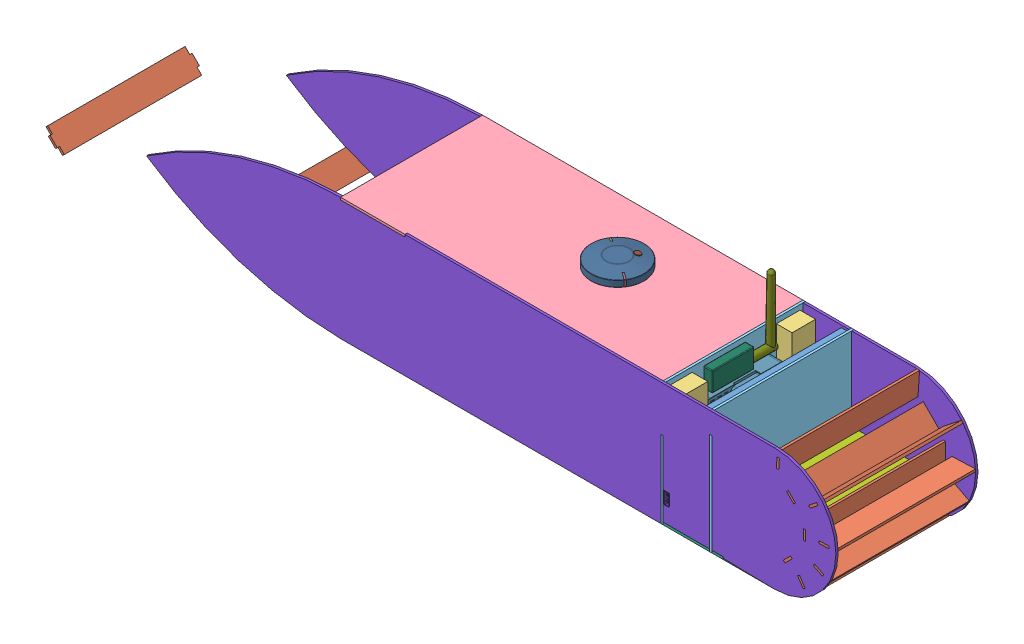
SolidWorks assembly payload_assembly, configuration Default. Lengths in mm.
Overall size (902.45 257.73 438.02).
36 component instances, 21 part files, 60 mates.
Components (placement in the parent):
- payload_box-1: payload_box [Default] at origin size (305 130 155)
- payload_parachute-1: payload_parachute [Default] at (305 0 0) x (0 0 -1) z (1 0 0) size (155 130 80)
- plates_payload_spacer-1: plates_payload_spacer [Default] at (-10 -10 10) x (0 0 -1) z (0 -1 0) size (175 405 150)
- plate_top-1: plate_top [Default] at (-10 140 10) x (0 0 1) z (0 1 0) size (181 411 3)
- plate_vertical-1: plate_vertical [Default] at (385 0 0) x (0 0 -1) z (1 0 0) size (181 156 3)
- plate_horizontal_front-1: plate_horizontal_front [Default] at (395 -13 13) size (144.93 3 181)
- battery-1: battery [Default] at (459.93 -89.8623 1.4153) x (0 0 -1) z (1 0 0) size (170 50 80)
- plate_side-2: plate_side [Default] at (-260.0699 -13 -168) x (1 0 0) z (0 -1 0) size (878 3 156)
- plate_side-5: plate_side [Default] at (-260.0699 -13 10) x (1 0 0) z (0 -1 0) size (878 3 156)
- Buzzer-1: Buzzer [Default] at (398 15.3505 -147.1593) x (0 -1 0) z (0 0 1) size (44.4 5.16 29.86)
- HERE GPS-1: HERE GPS [Default] at (243.7386 143 -83.1609) x (-0.837169 0 -0.546944) z (0 1 0) size (67.24 67.23 17.04)
  - HERE GPS.iges-1: HERE GPS.iges [Default] at origin size (67.24 67.23 17.04)
    - Component1.iges-1: Component1.iges [Default] at origin size (67.22 67.23 16.8)
    - Component2.iges-1: Component2.iges [Default] at origin size (8.5 8.84 4.72)
    - Component3.iges-1: Component3.iges [Default] at origin size (8.53 2.03 12.07)
    - Component5.iges-1: Component5.iges [Default] at origin size (8.63 2.03 12.07)
- Pixhawk2.1 CUBE with Edison carrier-1: Pixhawk2.1 CUBE with Edison carrier [Default] at (398 86.4256 -77.5) x (0 0 -1) z (1 0 0) size (94.25 44.2 30.94)
- Transmitter-1: Transmitter [Default] at (409.5873 129.6354 -50.6064) x (0 0 1) z (0 -1 0) size (85.99 11.87 93.47)
  - Transmitter Body-1: Transmitter Body [Default] at (-14.2095 0.1873 5.1078) size (59.4 11.4 25)
  - Transmitter Antenna-1: Transmitter Antenna [Default] at (-41.6595 7.0523 10.0828) x (0 -0.010581 -0.999944) z (0 0.999944 -0.010581) size (90.85 31.89 9.9)
- XT60E-M-1: XT60E-M [Default] at (402.1 17.8234 6) size (8.2 27.2 16.5)
- RaspberryPi as part-1: RaspberryPi as part [Default] at (401 18 -77.5) x (0 0 1) z (0 1 0) size (89.62 18.75 58.3)
- plate_vertical-2: plate_vertical [Default] at (446.93 0 0) x (0 0 -1) z (1 0 0) size (181 156 3)
- electronics_cushion-1: electronics_cushion [Default] at (456.93 -10 -165) x (0 0 1) z (0 -1 0) size (175 10 150)
- support_plates-1: support_plates [Default] at (570.2912 87.207 13) x (0 0 -1) z (0.707107 0.707107 0) size (181 30 3)
- ESC-3: ESC [Default] at (398 136.8447 -131.1379) x (0 -1 0) z (0 0 1) size (90 20 30)
- ESC-5: ESC [Default] at (398 136.8447 6.1379) x (0 -1 0) z (0 0 1) size (90 20 30)
- support_plates-7: support_plates [Default] at (579.3866 80.8169 13) x (0 0 -1) z (-1 0 0) size (181 30 3)
- support_plates-9: support_plates [Default] at (567.1217 25.4338 13) x (0 0 -1) z (-0.841434 -0.540359 0) size (181 30 3)
- support_plates-12: support_plates [Default] at (587.8173 68.4184 13) x (0 0 -1) z (0.040003 -0.9992 0) size (181 30 3)
- support_plates-14: support_plates [Default] at (583.2011 44.2036 13) x (0 0 -1) z (-0.461126 -0.887335 0) size (181 30 3)
- support_plates-15: support_plates [Default] at (576.5975 95.9898 13) x (0 0 -1) z (0.621321 -0.783556 0) size (181 30 3)
- support_plates-16: support_plates [Default] at (541.5439 112.9819 13) x (0 0 -1) z (0.997897 -0.064824 0) size (181 30 3)
- support_plates-19: support_plates [Default] at (568.3493 37.745 13) x (0 0 -1) z (-0.707107 0.707107 0) size (181 30 3)
- support_plates-20: support_plates [Default] at (-263.3078 115.5649 119.621) x (0 0 -1) z (0.707107 0.707107 0) size (181 30 3)
- support_plates-21: support_plates [Default] at (-217.4292 -52.2343 -137.4006) x (0 0 -1) z (0.707107 0.707107 0) size (181 30 3)
Mates (geometry in assembly coordinates):
- InPlace1: in place: plane of payload_box-1 through (305 130 0) normal (1 0 0); plane of payload_parachute-1 through (305 0 0) normal (1 0 0); moOrthogonalPlaneRef_w of payload_box-1 through (305 130 0) normal (1 0 0); plane of payload_parachute-1 through (305 0 0) normal (0 1 0); plane of payload_box-1 through (305 130 0) normal (1 0 0); plane of payload_parachute-1 through (305 0 0) normal (0 0 -1); plane of payload_box-1 through (305 130 0) normal (1 0 0); unknown of payload_parachute-1
- Coincident1: coincident aligned: plane of ?; plane of ?
- Coincident2: coincident aligned: moOrthogonalPlaneRef_w of payload_box-1 through (305 0 0) normal (0 1 0); plane of Part2^Assem1-1 through (305 0 0) normal (0 1 0)
- Coincident3: coincident anti-aligned: moOrthogonalPlaneRef_w of payload_box-1 through (305 0 0) normal (0 0 1); plane of Part2^Assem1-1 through (305 0 0) normal (0 0 -1)
- Width1: width anti-aligned: plane of plates_payload_spacer-1 through (395 -10 -165) normal (0 0 -1); plane of payload_box-1 through (395 -10 10) normal (0 0 1); plane of plates_payload_spacer-1 through (0 130 0) normal (0 0 1); plane of payload_box-1 through (0 130 -155) normal (0 0 -1)
- Width2: width anti-aligned: plane of plates_payload_spacer-1 through (395 -10 10) normal (0 -1 0); plane of payload_box-1 through (395 140 10) normal (0 1 0); plane of plates_payload_spacer-1 through (0 130 0) normal (0 1 0); plane of payload_box-1 through (0 0 0) normal (0 -1 0)
- Width3: width anti-aligned: plane of plates_payload_spacer-1 through (-10 -10 10) normal (-1 0 0); plane of payload_parachute-1 through (395 -10 10) normal (1 0 0); plane of plates_payload_spacer-1 through (385 0 0) normal (1 0 0); plane of payload_box-1 through (0 130 0) normal (-1 0 0)
- InPlace2: in place: plane of plates_payload_spacer-1 through (395 140 10) normal (0 1 0); plane of ? through (0 140 0) normal (0 1 0); plane of plates_payload_spacer-1 through (395 140 10) normal (0 1 0); plane of ? through (0 140 0) normal (0 0 -1); plane of plates_payload_spacer-1 through (395 140 10) normal (0 1 0); plane of ? through (0 140 0) normal (1 0 0); plane of plates_payload_spacer-1 through (395 140 10) normal (0 1 0); unknown of plate_top-1
- Coincident4: coincident aligned: plane of ?; plane of ?
- Coincident5: coincident aligned: moOrthogonalPlaneRef_w of plates_payload_spacer-1 through (-10 140 10) normal (1 0 0); plane of plate_top-1 through (-10 140 10) normal (1 0 0)
- Coincident6: coincident anti-aligned: moOrthogonalPlaneRef_w of plates_payload_spacer-1 through (-10 140 10) normal (0 0 -1); plane of plate_top-1 through (-10 140 10) normal (0 0 1)
- InPlace3: in place: plane of payload_parachute-1 through (385 0 0) normal (1 0 0); plane of plate_vertical-1 through (385 0 0) normal (1 0 0); plane of payload_parachute-1 through (385 0 0) normal (1 0 0); plane of plate_vertical-1 through (385 0 0) normal (0 1 0); plane of payload_parachute-1 through (385 0 0) normal (1 0 0); plane of plate_vertical-1 through (385 0 0) normal (0 0 -1); plane of payload_parachute-1 through (385 0 0) normal (1 0 0); unknown of plate_vertical-1
- Coincident7: coincident aligned: plane of ?; plane of ?
- Coincident8: coincident aligned: moOrthogonalPlaneRef_w of payload_parachute-1 through (385 0 0) normal (0 1 0); plane of Part5^payload_assembly-1 through (385 0 0) normal (0 1 0)
- Coincident9: coincident anti-aligned: moOrthogonalPlaneRef_w of payload_parachute-1 through (385 0 0) normal (0 0 1); plane of Part5^payload_assembly-1 through (385 0 0) normal (0 0 -1)
- Coincident10: coincident aligned: plane of Part5^payload_assembly-1 through (398 -13 13) normal (0 -1 0); plane of plate_horizontal_front-1 through (395 -13 13) normal (0 -1 0)
- Coincident11: coincident aligned: plane of Part5^payload_assembly-1 through (398 -13 -168) normal (0 0 -1); plane of plate_horizontal_front-1 through (395 -10 -168) normal (0 0 -1)
- Coincident12: coincident aligned: plane of Part5^payload_assembly-1 through (395 0 0) normal (-1 0 0); plane of plate_horizontal_front-1 through (395 -10 13) normal (-1 0 0)
- Coincident14: coincident anti-aligned: plane of plates_payload_spacer-1 through (395 -10 -165) normal (0 0 -1); plane of plate_side-2 through (539.9301 65 -165) normal (0 0 1)
- Coincident15: coincident aligned: plane of plate_top-1 through (-10 143 10) normal (0 1 0); plane of plate_side-2 through (-13 143 -165) normal (0 1 0)
- Coincident17: coincident anti-aligned: plane of plate_horizontal_front-1 through (395 -10 13) normal (0 1 0); plane of battery-1 through (539.93 -10 7.5) normal (0 -1 0)
- Width5: width anti-aligned: plane of battery-1 through (539.93 40 -162.5) normal (0 0 -1); plane of battery-1 through (539.93 40 7.5) normal (0 0 1); plane of plate_horizontal_front-1 through (395 -10 13) normal (0 0 1); plane of plate_horizontal_front-1 through (395 -10 -168) normal (0 0 -1)
- Coincident18: coincident anti-aligned: plane of plate_vertical-1 through (398 0 0) normal (1 0 0); plane of Pixhawk2.1 CUBE with Edison carrier-1 through (398 86.4256 -77.5) normal (-1 0 0)
- Width7: width aligned: plane of Pixhawk2.1 CUBE with Edison carrier-1 through (398 69.3256 -124.625) normal (0 0 -1); plane of Pixhawk2.1 CUBE with Edison carrier-1 through (398 103.5256 -30.375) normal (0 0 1); plane of plate_vertical-1 through (398 -13 -168) normal (0 0 -1); plane of plate_vertical-1 through (398 143 13) normal (0 0 1)
- Coincident21: coincident anti-aligned: plane of plate_vertical-1 through (398 0 0) normal (1 0 0); plane of RaspberryPi as part-1 through (398 -5.355 -81.25) normal (-1 0 0)
- Width8: width anti-aligned: plane of RaspberryPi as part-1 through (399.7 43.5 -35) normal (0 0 1); plane of RaspberryPi as part-1 through (399.7 -7.5 -120) normal (0 0 -1); plane of plate_vertical-1 through (398 -13 -168) normal (0 0 -1); plane of plate_vertical-1 through (398 143 13) normal (0 0 1)
- Coincident25: coincident anti-aligned: plane of plate_vertical-1 through (398 0 0) normal (1 0 0); plane of Buzzer-1 through (398 15.3505 -147.1593) normal (-1 0 0)
- Coincident26: coincident anti-aligned: plane of plate_horizontal_front-1 through (395 -10 13) normal (0 1 0); plane of RaspberryPi as part-1 through (399.7 -10 -37.5) normal (0 -1 0)
- Coincident31: coincident anti-aligned: plane of plate_vertical-1 through (398 0 0) normal (1 0 0); plane of XT60E-M-1 through (398 30.4234 10) normal (-1 0 0)
- Coincident34: coincident anti-aligned: plane of plate_vertical-1 through (398 0 0) normal (1 0 0); plane of Transmitter-1/Transmitter Body-1 through (398 124.5276 -64.8159) normal (-1 0 0)
- Parallel2: parallel anti-aligned: plane of plate_horizontal_front-1 through (395 -10 13) normal (0 1 0); plane of Transmitter-1/Transmitter Body-1 through (398 112.0276 -91.4659) normal (0 -1 0)
- Coincident35: coincident aligned: line of plate_vertical-1 through (398 143 13) axis (0 -1 0); line of XT60E-M-1 through (398 25.6734 13) axis (0 -1 0)
- Coincident36: coincident aligned: plane of plate_horizontal_front-1 through (395 -10 13) normal (0 0 1); plane of plate_vertical-2 through (459.93 143 13) normal (0 0 1)
- Coincident37: coincident aligned: plane of plate_horizontal_front-1 through (395 -13 13) normal (0 -1 0); plane of plate_vertical-2 through (459.93 -13 13) normal (0 -1 0)
- Coincident39: coincident anti-aligned: plane of battery-1 through (459.93 -89.8623 1.4153) normal (-1 0 0); plane of plate_vertical-2 through (459.93 0 0) normal (1 0 0)
- Coincident40: coincident anti-aligned: line of plate_top-1 through (-13 143 -168) axis (0 0 1); line of plate_side-2 through (-13 143 -165) axis (0 0 -1)
- Coincident45: coincident aligned: line of plate_horizontal_front-1 through (539.93 -10 13) axis (0 0 -1); line of battery-1 through (539.93 -10 7.5) axis (0 0 -1)
- Tangent4: tangent anti-aligned: plane of plate_top-1 through (-10 143 10) normal (0 1 0); face of ?
- Coincident46: coincident anti-aligned: plane of plate_horizontal_front-1 through (395 -10 13) normal (0 1 0); plane of electronics_cushion-1 through (446.93 -10 -165) normal (0 -1 0)
- Coincident47: coincident anti-aligned: plane of plate_vertical-2 through (456.93 0 0) normal (-1 0 0); plane of electronics_cushion-1 through (456.93 -10 -165) normal (1 0 0)
- Coincident48: coincident anti-aligned: plane of plate_side-2 through (539.9301 65 -165) normal (0 0 1); plane of electronics_cushion-1 through (446.93 -10 -165) normal (0 0 -1)
- Coincident49: coincident aligned: plane of plate_side-2 through (539.9301 65 -168) normal (0 0 -1); plane of support_plates-1 through (557.2097 104.5311 -168) normal (0 0 -1)
- Coincident52: coincident anti-aligned: plane of plate_vertical-1 through (398 0 0) normal (1 0 0); plane of ESC-3 through (398 136.8447 -131.1379) normal (-1 0 0)
- Coincident54: coincident aligned: plane of support_plates-1 through (557.2097 104.5311 -168) normal (0 0 -1); plane of support_plates-7 through (576.3866 59.3169 -168) normal (0 0 -1)
- Coincident57: coincident aligned: plane of plate_side-2 through (539.9301 65 -168) normal (0 0 -1); plane of support_plates-9 through (576.2152 5.7219 -168) normal (0 0 -1)
- Coincident59: coincident: circle of plate_side-5; point of support_plates-9
- Coincident60: coincident: circle of plate_side-5; point of support_plates-9
- Coincident62: coincident aligned: plane of plate_side-2 through (539.9301 65 -168) normal (0 0 -1); plane of support_plates-12 through (609.4201 66.2808 -168) normal (0 0 -1)
- Coincident63: coincident: circle of plate_side-5; point of support_plates-12
- Coincident64: coincident: circle of plate_side-5; point of support_plates-12
- Coincident68: coincident aligned: plane of plate_side-2 through (539.9301 65 -168) normal (0 0 -1); plane of support_plates-14 through (600.8954 31.6274 -168) normal (0 0 -1)
- Coincident69: coincident: circle of plate_side-5; point of support_plates-14
- Coincident70: coincident: circle of plate_side-5; point of support_plates-14
- Coincident71: coincident aligned: plane of plate_side-2 through (539.9301 65 -168) normal (0 0 -1); plane of support_plates-15 through (595.3079 106.9975 -168) normal (0 0 -1)
- Coincident72: coincident: circle of plate_side-5; point of support_plates-15
- Coincident73: coincident: circle of plate_side-5; point of support_plates-15
- Coincident74: coincident aligned: plane of plate_side-2 through (539.9301 65 -168) normal (0 0 -1); plane of support_plates-16 through (545.9313 134.2422 -168) normal (0 0 -1)
- Coincident75: coincident: circle of plate_side-5; point of support_plates-16
- Coincident76: coincident: circle of plate_side-5; point of support_plates-16
- Coincident83: coincident aligned: plane of plate_side-2 through (539.9301 65 -168) normal (0 0 -1); plane of support_plates-19 through (551.0252 24.6635 -168) normal (0 0 -1)
